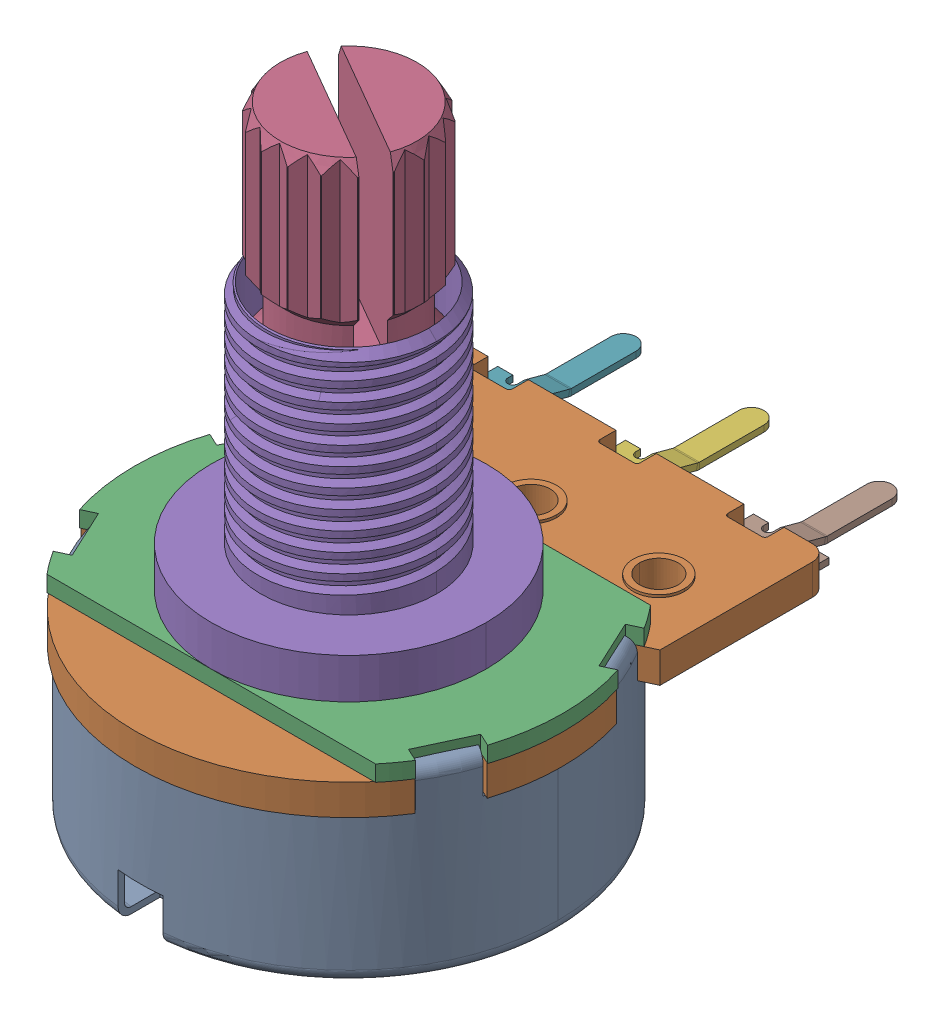
SolidWorks assembly P160KN, configuration Default. Lengths in mm.
Overall size (17.02 24.51 25.03).
8 component instances, 6 part files, 0 mates.
Components (placement in the parent):
- BM-251-1: BM-251 [Default] at origin size (16.64 7.4 16.64)
- BM-252-1: BM-252 [Default] at (0 5.8674 0) size (16.94 1.32 19.9)
- BM-253-1: BM-253 [Default] at (0 7.0866 0) size (17.02 0.64 10.92)
- BM-239-12-1: BM-239-12 [Default] at (0 14.301 0) x (-0.866025 0 -0.5) z (0.5 0 -0.866025) size (6 15.21 6)
- BM-254-1-1: BM-254-1 [Default] at (0 7.7216 0) size (10.92 10.59 10.92)
- BM-396-1: BM-396 [Default] at (0 4.0231 -7.4352) x (-1 0 0) z (0 0.258819 -0.965926) size (3 3.24 10.4)
- BM-396-2: BM-396 [Default] at (-5.08 4.0231 -7.4352) x (-1 0 0) z (0 0.258819 -0.965926) size (3 3.24 10.4)
- BM-396-3: BM-396 [Default] at (5.08 4.0231 -7.4352) x (-1 0 0) z (0 0.258819 -0.965926) size (3 3.24 10.4)
